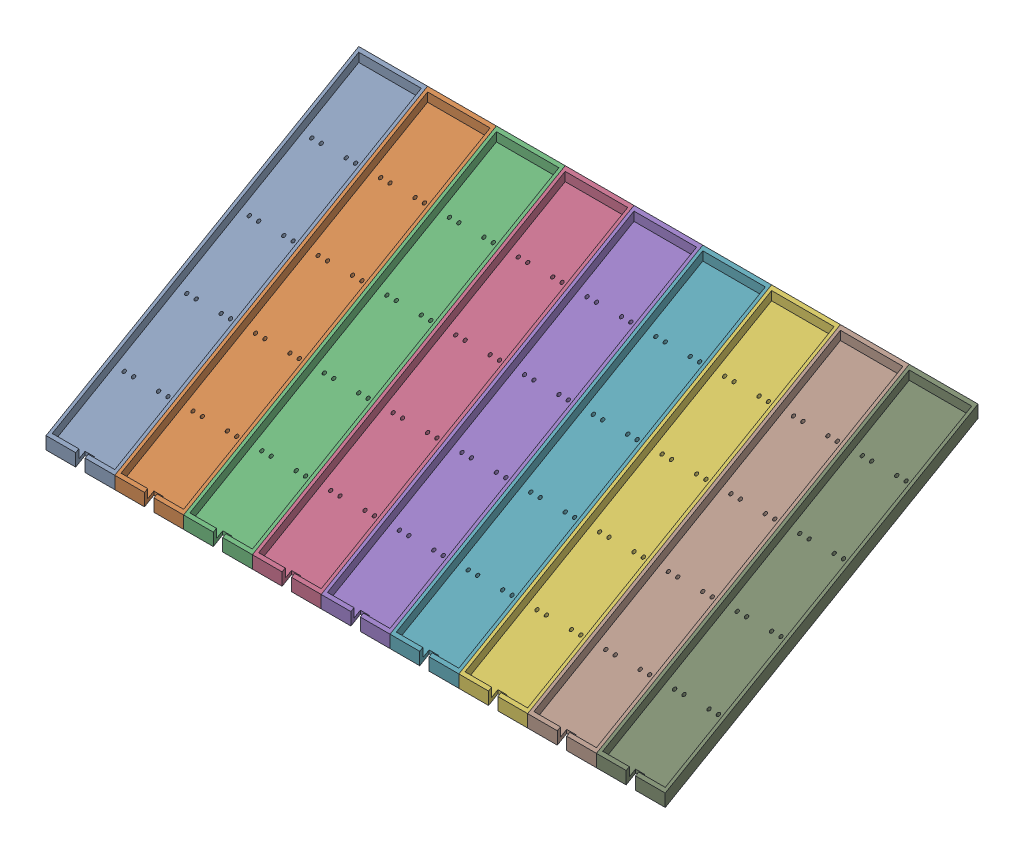
SolidWorks assembly shelves_rows, configuration Default. Lengths in mm.
Overall size (990 308.68 500).
9 component instances, 1 part files, 16 mates.
Components (placement in the parent):
- shelf-2: shelf [Default] at (42.1349 -122.0915 292.9267) x (-1 0 0) z (0 0 -1) size (110 308.68 500)
- shelf-3: shelf [Default] at (152.1349 -122.0915 292.9267) x (-1 0 0) z (0 0 -1) size (110 308.68 500)
- shelf-4: shelf [Default] at (262.1349 -122.0915 292.9267) x (-1 0 0) z (0 0 -1) size (110 308.68 500)
- shelf-5: shelf [Default] at (372.1349 -122.0915 292.9267) x (-1 0 0) z (0 0 -1) size (110 308.68 500)
- shelf-6: shelf [Default] at (482.1349 -122.0915 292.9267) x (-1 0 0) z (0 0 -1) size (110 308.68 500)
- shelf-7: shelf [Default] at (702.1349 -122.0915 292.9267) x (-1 0 0) z (0 0 -1) size (110 308.68 500)
- shelf-8: shelf [Default] at (592.1349 -122.0915 292.9267) x (-1 0 0) z (0 0 -1) size (110 308.68 500)
- shelf-9: shelf [Default] at (812.1349 -122.0915 292.9267) x (-1 0 0) z (0 0 -1) size (110 308.68 500)
- shelf-10: shelf [Default] at (922.1349 -122.0915 292.9267) x (-1 0 0) z (0 0 -1) size (110 308.68 500)
Mates (geometry in assembly coordinates):
- Coincident4: coincident aligned: line of shelf-2 through (42.1349 -122.0915 292.9267) axis (0 1 0); line of shelf-3 through (42.1349 -122.0915 292.9267) axis (0 1 0)
- Coincident5: coincident aligned: line of shelf-2 through (42.1349 -102.0915 292.9267) axis (0 0.5 -0.866025); line of shelf-3 through (42.1349 -102.0915 292.9267) axis (0 0.5 -0.866025)
- Coincident6: coincident aligned: line of shelf-3 through (152.1349 -102.0915 292.9267) axis (0 0.5 -0.866025); line of shelf-4 through (152.1349 -102.0915 292.9267) axis (0 0.5 -0.866025)
- Coincident7: coincident aligned: line of shelf-3 through (152.1349 -122.0915 292.9267) axis (0 1 0); line of shelf-4 through (152.1349 -122.0915 292.9267) axis (0 1 0)
- Coincident8: coincident aligned: line of shelf-4 through (262.1349 -102.0915 292.9267) axis (0 0.5 -0.866025); line of shelf-5 through (262.1349 -102.0915 292.9267) axis (0 0.5 -0.866025)
- Coincident9: coincident aligned: line of shelf-4 through (262.1349 -122.0915 292.9267) axis (0 1 0); line of shelf-5 through (262.1349 -122.0915 292.9267) axis (0 1 0)
- Coincident10: coincident aligned: line of shelf-5 through (372.1349 -102.0915 292.9267) axis (0 0.5 -0.866025); line of shelf-6 through (372.1349 -102.0915 292.9267) axis (0 0.5 -0.866025)
- Coincident13: coincident: point of shelf-5; unknown of shelf-6
- Coincident14: coincident aligned: line of shelf-6 through (482.1349 -102.0915 292.9267) axis (0 0.5 -0.866025); line of shelf-8 through (482.1349 -102.0915 292.9267) axis (0 0.5 -0.866025)
- Coincident15: coincident aligned: line of shelf-6 through (482.1349 -122.0915 292.9267) axis (0 1 0); line of shelf-8 through (482.1349 -122.0915 292.9267) axis (0 1 0)
- Coincident16: coincident aligned: line of shelf-7 through (592.1349 -102.0915 292.9267) axis (0 0.5 -0.866025); line of shelf-8 through (592.1349 -102.0915 292.9267) axis (0 0.5 -0.866025)
- Coincident17: coincident aligned: line of shelf-7 through (592.1349 -122.0915 292.9267) axis (0 1 0); line of shelf-8 through (592.1349 -122.0915 292.9267) axis (0 1 0)
- Coincident18: coincident aligned: line of shelf-7 through (702.1349 -102.0915 292.9267) axis (0 0.5 -0.866025); line of shelf-9 through (702.1349 -102.0915 292.9267) axis (0 0.5 -0.866025)
- Coincident19: coincident aligned: line of shelf-7 through (702.1349 -122.0915 292.9267) axis (0 1 0); line of shelf-9 through (702.1349 -122.0915 292.9267) axis (0 1 0)
- Coincident20: coincident aligned: line of shelf-9 through (812.1349 -102.0915 292.9267) axis (0 0.5 -0.866025); line of shelf-10 through (812.1349 -102.0915 292.9267) axis (0 0.5 -0.866025)
- Coincident21: coincident aligned: line of shelf-9 through (812.1349 -122.0915 292.9267) axis (0 1 0); line of shelf-10 through (812.1349 -122.0915 292.9267) axis (0 1 0)
